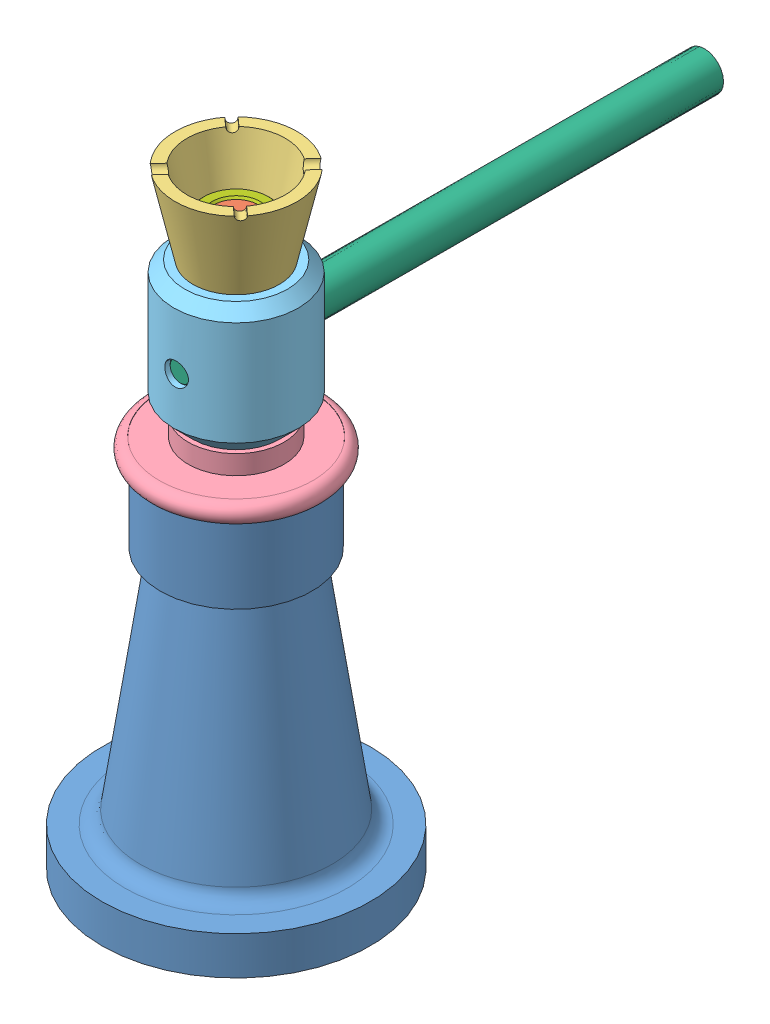
SolidWorks assembly Assem2, configuration Default. Lengths in mm.
Overall size (140 317.21 314.97).
7 component instances, 7 part files, 13 mates.
Components (placement in the parent):
- Body-SJ-1: Body-SJ [Default] at (135.0225 128.0569 85.7835) size (140 185 140)
- CSK-SJ-1: CSK-SJ [Default] at (135.0225 302.2197 85.7835) x (0 -1 0) z (-0.839731 0 -0.543003) size (30 24 24)
- Cup-SJ-1: Cup-SJ [Default] at (135.0225 279.9482 85.7835) x (0.666973 0 -0.745082) z (0.745082 0 0.666973) size (63.53 42.21 63.61)
- Nut-SJ-1: Nut-SJ [Default] at (135.0225 174.5887 85.7835) x (-0.276574 0 0.960992) z (-0.960992 0 -0.276574) size (90.17 45 90.17)
- Spindle-SJ-1: Spindle-SJ [Default] at (135.0225 122.1841 85.7835) x (0 -1 0) z (0.999994 0 0.00343) size (240 65 65)
- Tommy-PJ-1: Tommy-PJ [Default] at (136.5502 243.7782 -65.467) x (0.00343 0 -0.999994) z (0.999994 0 0.00343) size (275 20 20)
- Washer-PJ-1: Washer-PJ [Default] at (135.0225 328.0031 85.7835) x (0 -1 0) z (-0.516083 0 0.856539) size (8 35 35)
Mates (geometry in assembly coordinates):
- Concentric2: concentric aligned: cylinder of Body-SJ-1 through (135.0225 204.2306 85.7835) axis (0 1 0) radius 25; cylinder of Spindle-SJ-1 through (135.0225 291.7782 85.7835) axis (0 1 0) radius 19
- Concentric3: concentric aligned: cylinder of Nut-SJ-1 through (135.0225 231.3865 85.7835) axis (0 1 0) radius 19; cylinder of Spindle-SJ-1 through (135.0225 291.7782 85.7835) axis (0 1 0) radius 19
- Concentric4: concentric aligned: cylinder of Body-SJ-1 through (135.0225 204.2306 85.7835) axis (0 1 0) radius 25; cylinder of Nut-SJ-1 through (135.0225 231.3865 85.7835) axis (0 1 0) radius 25
- Coincident2: coincident anti-aligned: plane of Body-SJ-1 through (174.6103 188.7782 85.7835) normal (0 1 0); plane of Nut-SJ-1 through (128.1081 188.7782 109.8083) normal (0 -1 0)
- Coincident4: coincident anti-aligned: plane of Nut-SJ-1 through (129.7675 208.7782 104.0424) normal (0 1 0); plane of Spindle-SJ-1 through (135.0876 208.7782 66.7836) normal (0 -1 0)
- Concentric5: concentric aligned: cylinder of Cup-SJ-1 through (135.0225 309.0851 85.7835) axis (0 1 0) radius 11.25; cylinder of Spindle-SJ-1 through (135.0225 291.7782 85.7835) axis (0 1 0) radius 11
- Coincident6: coincident anti-aligned: plane of Cup-SJ-1 through (142.5259 278.7782 77.4013) normal (0 -1 0); plane of Spindle-SJ-1 through (135.1145 278.7782 58.9568) normal (0 1 0)
- Concentric8: concentric anti-aligned: cylinder of Spindle-SJ-1 through (135.9199 243.7782 118.2868) axis (0.00343 0 -0.999994) radius 6; cylinder of Tommy-PJ-1 through (135.9283 243.7782 115.8424) axis (-0.00343 0 0.999994) radius 6
- Tangent2: tangent anti-aligned: cylinder of Spindle-SJ-1 through (135.0225 291.7782 85.7835) axis (0 1 0) radius 32.5; plane of Tommy-PJ-1 through (136.1429 251.5865 53.2872) normal (-0.00343 0 0.999994)
- Concentric9: concentric aligned: cylinder of Spindle-SJ-1 through (135.0225 291.7782 85.7835) axis (0 1 0) radius 11; cylinder of Washer-PJ-1 through (135.0225 386.757 85.7835) axis (0 1 0) radius 7.25
- Coincident7: coincident anti-aligned: plane of Cup-SJ-1 through (147.6949 290.7782 71.6269) normal (0 1 0); plane of Washer-PJ-1 through (141.2324 290.7782 89.5251) normal (0 -1 0)
- Concentric11: concentric: cylinder of CSK-SJ-1 through (135.0225 324.22 85.7835) axis (0 1 0) radius 6; cylinder of Spindle-SJ-1 through (135.0225 261.7782 85.7835) axis (0 1 0) radius 6
- Coincident8: coincident aligned: circle of CSK-SJ-1; circle of Spindle-SJ-1
